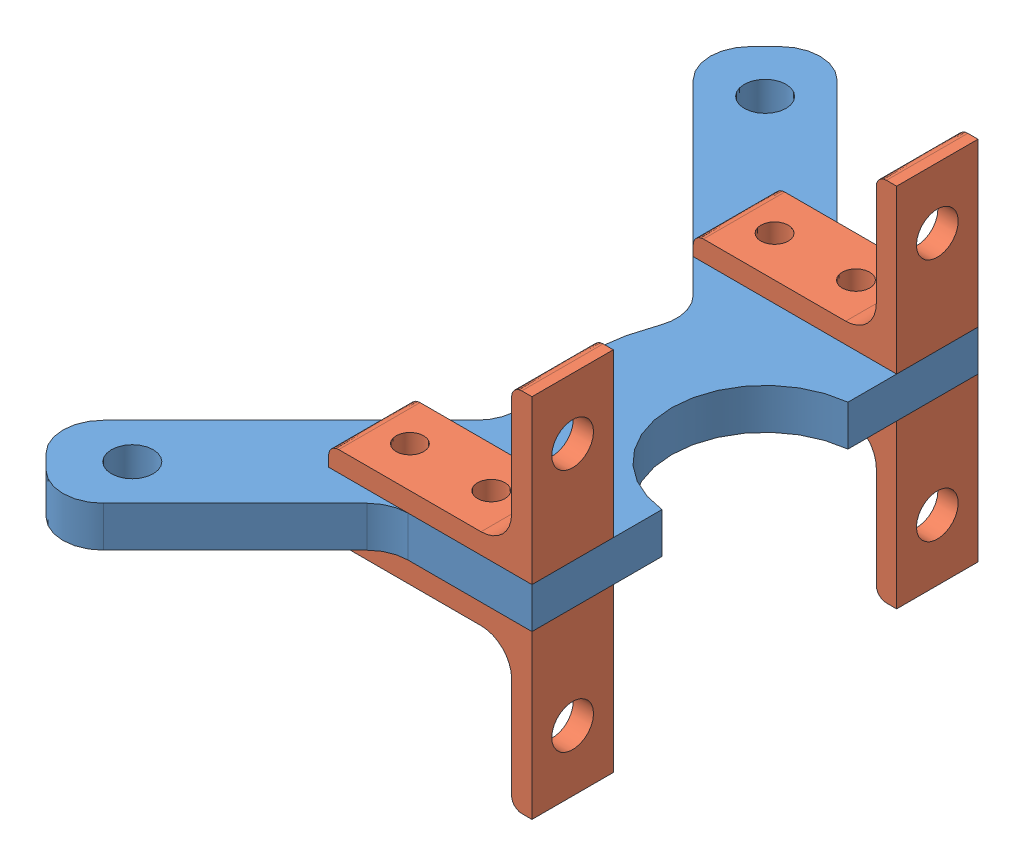
SolidWorks assembly RegRing_Assy, configuration Default. Lengths in mm.
Overall size (145.48 57.15 145.48).
5 component instances, 2 part files, 3 mates.
Components (placement in the parent):
- RegRing-1: RegRing [Default] x (0.707107 0 -0.707107) z (0.707107 0 0.707107) size (102.87 6.35 102.87)
- TankRing_Bracket-1: TankRing_Bracket [8982K116] at (-17.4625 22.225 28.4622) size (31.75 25.4 12.7)
- TankRing_Bracket-2: TankRing_Bracket [8982K116] at (-17.4625 -15.875 28.4622) x (1 0 0) z (0 0 -1) size (31.75 25.4 12.7)
- TankRing_Bracket-3: TankRing_Bracket [8982K116] at (-17.4625 22.225 -28.4622) size (31.75 25.4 12.7)
- TankRing_Bracket-4: TankRing_Bracket [8982K116] at (-17.4625 -15.875 -28.4622) x (1 0 0) z (0 0 -1) size (31.75 25.4 12.7)
Mates (geometry in assembly coordinates):
- Concentric1: concentric aligned: cylinder of RegRing-1 through (-26.9875 6.35 28.4622) axis (0 1 0) radius 2.1526; cylinder of TankRing_Bracket-1 through (-26.9875 9.525 28.4622) axis (0 1 0) radius 2.1526
- Concentric2: concentric aligned: cylinder of RegRing-1 through (-14.2875 6.35 28.4622) axis (0 1 0) radius 2.1526; cylinder of TankRing_Bracket-1 through (-14.2875 9.525 28.4622) axis (0 1 0) radius 2.1526
- Coincident1: coincident anti-aligned: plane of RegRing-1 through (0 6.35 0) normal (0 1 0); plane of TankRing_Bracket-1 through (-33.3375 6.35 34.8122) normal (0 -1 0)
